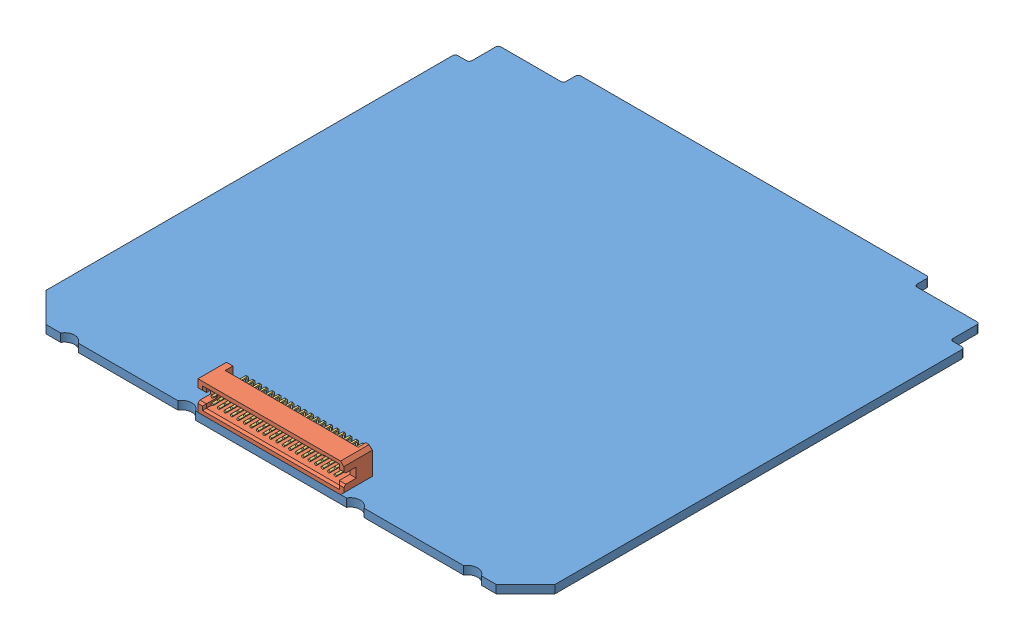
SolidWorks assembly ADACSCard_1U, configuration Default. Lengths in mm.
Overall size (99.8 7.62 107.17).
4 component instances, 3 part files, 13 mates.
Components (placement in the parent):
- ADACSPCB_1U-1: ADACSPCB_1U [Default] at origin size (99.8 1.6 107.17)
- TFM_120_01_L_D_RA-1: TFM_120_01_L_D_RA [Default] at (0 3.6575 39.237) x (1 0 0) z (0 -1 0) size (28.58 7.49 7.62)
  - _TFM_120_01_L_D_RA_terminal_2-1: _TFM_120_01_L_D_RA_terminal_2 [Default] at origin size (28.58 5.59 5.72)
  - _TFM_120_01_L_D_RA_pins_4-1: _TFM_120_01_L_D_RA_pins_4 [Default] at origin size (25.4 6.95 5.84)
Mates (geometry in assembly coordinates):
- Coincident1: coincident anti-aligned: plane of ADACSPCB_1U-1 through (0 0.8 0) normal (0 1 0); plane of TFM_120_01_L_D_RA-1/_TFM_120_01_L_D_RA_terminal_2-1 through (-14.2875 0.8 44.825) normal (0 -1 0)
- Coincident2: coincident: line of ADACSPCB_1U-1 through (49.9 0.8 37.332) axis (-1 0 0); plane of TFM_120_01_L_D_RA-1/_TFM_120_01_L_D_RA_pins_4-1 through (0 3.6575 37.332) normal (0 0 -1)
- Coincident3: coincident: line of ADACSPCB_1U-1 through (0 0.8 -5.2282) axis (0 0 1); plane of TFM_120_01_L_D_RA-1/_TFM_120_01_L_D_RA_terminal_2-1 through (0 3.6575 39.237) normal (1 0 0)
- Coincident4: coincident anti-aligned: plane of ADACSPCB_1U-1 through (0 0.8 0) normal (0 1 0); plane of TFM_110_01_L_D_RA_defeature-1 through (20.0625 0.8 44.825) normal (0 -1 0)
- Coincident5: coincident: line of ADACSPCB_1U-1 through (28 0.8 48.6679) axis (0 0 -1); plane of TFM_110_01_L_D_RA_defeature-1 through (28 3.6575 39.237) normal (1 0 0)
- Coincident6: coincident: line of ADACSPCB_1U-1 through (49.9 0.8 37.332) axis (-1 0 0); plane of TFM_110_01_L_D_RA_defeature-1 through (28 3.6575 37.332) normal (0 0 -1)
- Coincident7: coincident aligned: plane of Linear Short-1/Linear Magnetorquer-1 through (0 17.8 0) normal (1 0 0)
- Coincident12: coincident aligned: plane of Linear Short-1/Linear Magnetorquer-1 through (0 17.8 0) normal (0 0 1)
- Coincident14: coincident anti-aligned: plane of ADACSPCB_1U-1 through (0 0.8 0) normal (0 1 0); plane of Linear Short-1/Bracket base-2 through (-5 0.8 -24.76) normal (0 -1 0)
- Concentric1: concentric aligned: circle of ADCScard-1; circle of 94150A115_316 STAINLESS STEEL HEX NUT-1
- Coincident15: coincident anti-aligned: plane of ADACSPCB_1U-1 through (0 -0.8 0) normal (0 -1 0); plane of 94150A115_316 STAINLESS STEEL HEX NUT-1 through (-1.6798 -0.8 -28.0291) normal (0 1 0)
- Coincident17: coincident anti-aligned: plane of ADACSPCB_1U-1 through (0 -0.8 0) normal (0 -1 0); plane of 94150A115_316 STAINLESS STEEL HEX NUT-2 through (25.5802 -0.8 -0.7691) normal (0 1 0)
- Concentric2: concentric aligned: circle of ADCScard-1; circle of 94150A115_316 STAINLESS STEEL HEX NUT-2
